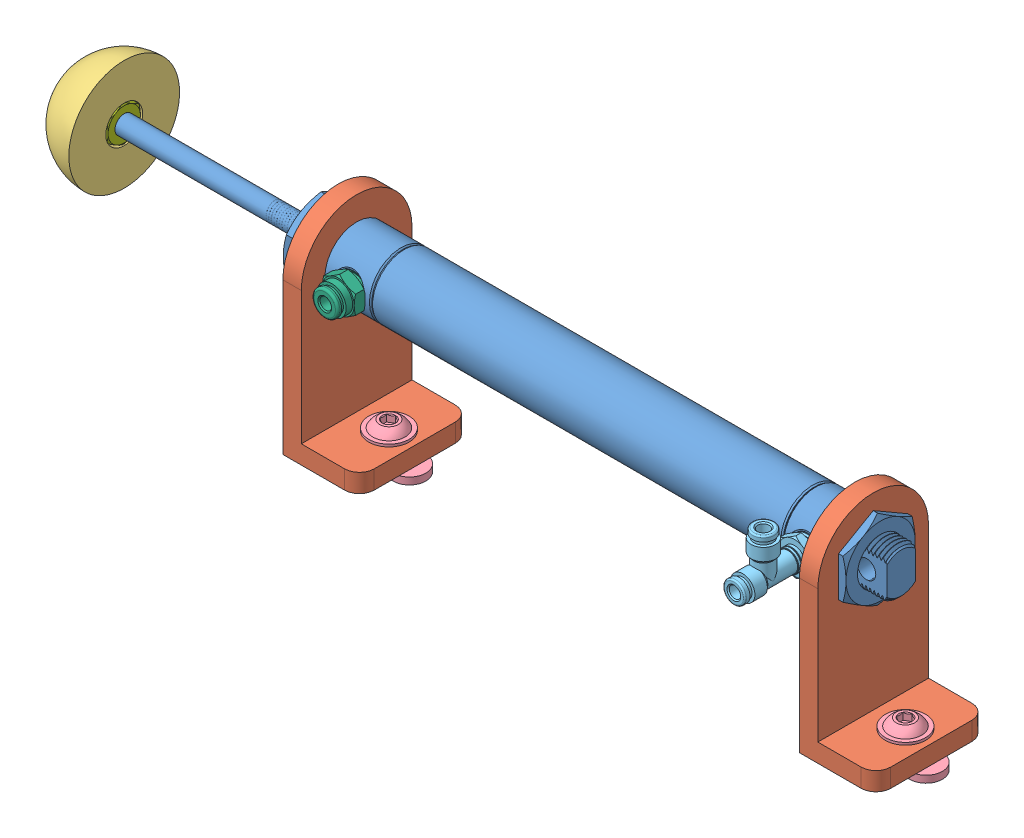
SolidWorks assembly CylinderSubAssembly, configuration Default. Lengths in mm.
Overall size (299.58 77.89 53.79).
10 component instances, 7 part files, 18 mates.
Components (placement in the parent):
- 6498K636_ROUND BODY AIR CYLINDER-1: 6498K636_ROUND BODY AIR CYLINDER [6498K636] at (125.5713 147.8721 280.6882) size (267.72 27.5 23.81)
- CylinderMount-1: CylinderMount [Default] at (40.1003 147.8721 280.6882) x (0 0 -1) z (1 0 0) size (38.1 71.12 26.35)
- CylinderMount-3: CylinderMount [Default] at (217.9003 147.8721 280.6882) x (0 0 -1) z (1 0 0) size (38.1 71.12 26.35)
- BagCompressorAttatchment-1: BagCompressorAttatchment [Default] at (-41.8941 147.8721 280.6882) x (0 1 0) z (0 0 1) size (38.1 17.96 38.1)
- 47065T142_ALUMINUM T-SLOTTED FRAMING EXTRUSION-1: 47065T142_ALUMINUM T-SLOTTED FRAMING EXTRUSION [47065T142] at (235.3628 102.1521 280.6882) size (25.4 16.7 13.87)
- 47065T142_ALUMINUM T-SLOTTED FRAMING EXTRUSION-2: 47065T142_ALUMINUM T-SLOTTED FRAMING EXTRUSION [47065T142] at (57.5628 102.1521 280.6882) size (25.4 16.7 13.87)
- 5779K201_PUSH-TO-CONNECT TUBE FITTING FOR AIR (1)-1: 5779K201_PUSH-TO-CONNECT TUBE FITTING FOR AIR (1) [5779K201] at (211.0423 147.8721 285.1055) x (1 0 0) z (0 0 -1) size (11 20.83 30.61)
- 5225K711_PUSH-TO-CONNECT TUBE FITTING FOR AIR (1)-4: 5225K711_PUSH-TO-CONNECT TUBE FITTING FOR AIR (1) [5225K711] at (54.5783 147.8721 284.5975) x (-1 0 0) z (0 0 -1) size (11 12.7 15.49)
- 95462A505_GRADE 5 STEEL HEX NUT-1: 95462A505_GRADE 5 STEEL HEX NUT [95462A505] at (-47.4503 147.8721 280.6882) x (0 0 -1) z (1 0 0) size (11.11 12.83 7.01)
- 95462A505_GRADE 5 STEEL HEX NUT-2: 95462A505_GRADE 5 STEEL HEX NUT [95462A505] at (-36.3378 147.8721 280.6882) x (0 0 -1) z (1 0 0) size (11.11 12.83 7.01)
Mates (geometry in assembly coordinates):
- Coincident1: coincident aligned: line of 6498K636_ROUND BODY AIR CYLINDER-1 through (36.2903 147.8721 280.6882) axis (-1 0 0); line of CylinderMount-1 through (46.4503 147.8721 280.6882) axis (-1 0 0)
- Distance1: distance = 2.54 mm aligned: plane of CylinderMount-1 through (40.1003 147.8721 280.6882) normal (-1 0 0); plane of 6498K636_ROUND BODY AIR CYLINDER-1 through (42.6403 136.9501 280.6882) normal (-1 0 0)
- Coincident5: coincident aligned: line of 6498K636_ROUND BODY AIR CYLINDER-1 through (36.2903 147.8721 280.6882) axis (-1 0 0); line of CylinderMount-3 through (224.2503 147.8721 280.6882) axis (-1 0 0)
- Distance3: distance = 171.45 mm anti-aligned: plane of CylinderMount-3 through (217.9003 147.8721 280.6882) normal (-1 0 0); plane of CylinderMount-1 through (46.4503 147.8721 280.6882) normal (1 0 0)
- Coincident7: coincident aligned: line of 6498K636_ROUND BODY AIR CYLINDER-1 through (36.2903 147.8721 280.6882) axis (-1 0 0); line of BagCompressorAttatchment-1 through (-39.116 147.8721 280.6882) axis (-1 0 0)
- Coincident8: coincident anti-aligned: plane of BagCompressorAttatchment-1 through (-33.5597 147.8721 280.6882) normal (1 0 0); plane of 6498K636_ROUND BODY AIR CYLINDER-1 through (-33.5597 147.8721 279.2552) normal (-1 0 0)
- Coincident9: coincident anti-aligned: line of CylinderMount-3 through (235.3628 95.8021 280.6882) axis (0 1 0); line of 47065T142_ALUMINUM T-SLOTTED FRAMING EXTRUSION-1 through (235.3628 102.9903 280.6882) axis (0 -1 0)
- Coincident10: coincident anti-aligned: plane of CylinderMount-3 through (217.9003 102.1521 280.6882) normal (0 1 0); plane of 47065T142_ALUMINUM T-SLOTTED FRAMING EXTRUSION-1 through (242.297 102.1521 280.6882) normal (0 -1 0)
- Coincident11: coincident anti-aligned: line of CylinderMount-1 through (57.5628 95.8021 280.6882) axis (0 1 0); line of 47065T142_ALUMINUM T-SLOTTED FRAMING EXTRUSION-2 through (57.5628 102.9903 280.6882) axis (0 -1 0)
- Coincident12: coincident anti-aligned: plane of CylinderMount-1 through (40.1003 102.1521 280.6882) normal (0 1 0); plane of 47065T142_ALUMINUM T-SLOTTED FRAMING EXTRUSION-2 through (64.497 102.1521 280.6882) normal (0 -1 0)
- Coincident13: coincident aligned: line of 6498K636_ROUND BODY AIR CYLINDER-1 through (211.0423 147.8721 291.6102) axis (0 0 -1); line of 5779K201_PUSH-TO-CONNECT TUBE FITTING FOR AIR (1)-1 through (211.0423 147.8721 293.0345) axis (0 0 -1)
- Distance4: distance = 25.4 mm: point of 5779K201_PUSH-TO-CONNECT TUBE FITTING FOR AIR (1)-1; moEndPointRef_w of 6498K636_ROUND BODY AIR CYLINDER-1
- Coincident16: coincident aligned: line of 6498K636_ROUND BODY AIR CYLINDER-1 through (54.5783 147.8721 291.6102) axis (0 0 -1); line of 5225K711_PUSH-TO-CONNECT TUBE FITTING FOR AIR (1)-4 through (54.5783 147.8721 285.5605) axis (0 0 -1)
- Distance5: distance = 1.27 mm anti-aligned: plane of 6498K636_ROUND BODY AIR CYLINDER-1 through (54.5783 147.8721 290.0305) normal (0 0 1); plane of 5225K711_PUSH-TO-CONNECT TUBE FITTING FOR AIR (1)-4 through (49.0783 157.3983 291.3005) normal (0 0 -1)
- Coincident17: coincident aligned: line of 6498K636_ROUND BODY AIR CYLINDER-1 through (36.2903 147.8721 280.6882) axis (-1 0 0); line of 95462A505_GRADE 5 STEEL HEX NUT-1 through (-44.4848 147.8721 280.6882) axis (-1 0 0)
- Coincident18: coincident anti-aligned: plane of BagCompressorAttatchment-1 through (-44.6722 147.8721 280.6882) normal (-1 0 0); plane of 95462A505_GRADE 5 STEEL HEX NUT-1 through (-44.6722 151.08 286.2445) normal (1 0 0)
- Coincident19: coincident aligned: line of 6498K636_ROUND BODY AIR CYLINDER-1 through (36.2903 147.8721 280.6882) axis (-1 0 0); line of 95462A505_GRADE 5 STEEL HEX NUT-2 through (-33.3723 147.8721 280.6882) axis (-1 0 0)
- Coincident20: coincident anti-aligned: plane of BagCompressorAttatchment-1 through (-39.116 147.8721 280.6882) normal (1 0 0); plane of 95462A505_GRADE 5 STEEL HEX NUT-2 through (-39.116 151.08 286.2445) normal (-1 0 0)
